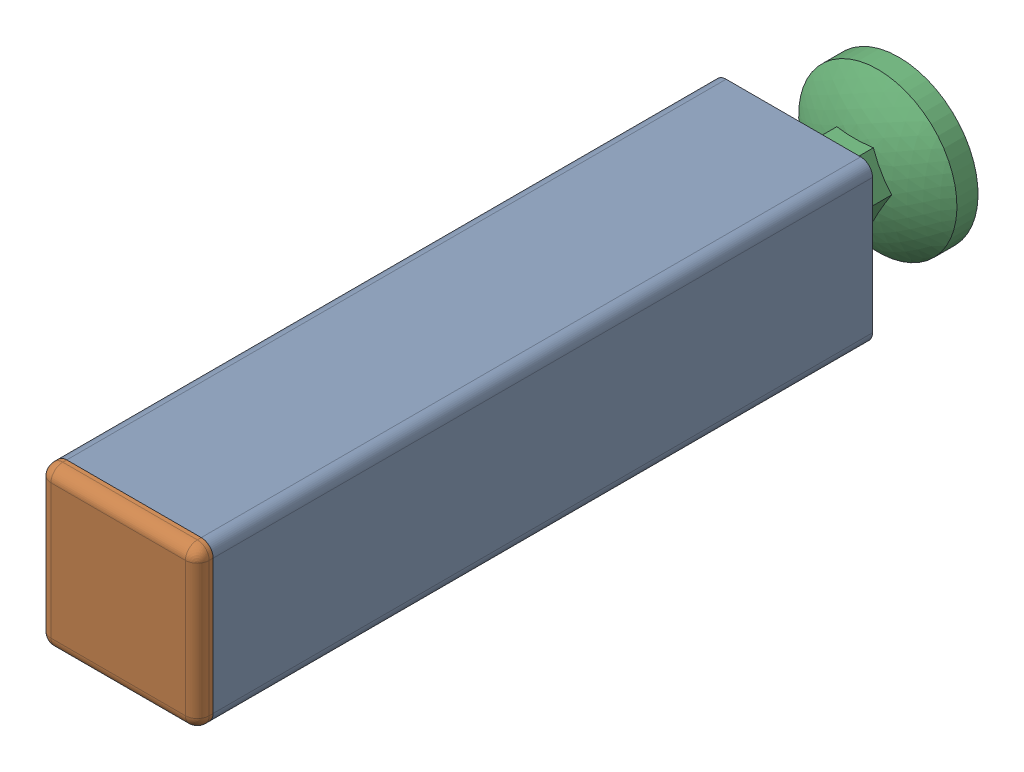
SolidWorks assembly AP_Poteau, configuration Défaut. Lengths in mm.
Overall size (30 30 148).
3 component instances, 3 part files, 5 mates.
Components (placement in the parent):
- Rexroth30x30x125-1: Rexroth30x30x125 [Défaut] at origin size (30 30 125)
- Rexroth-30x30_Chapeau-1: Rexroth-30x30_Chapeau [Défaut] at (0 0 125) size (30 30 3)
- Rexroth-PiedRotul8x30-1: Rexroth-PiedRotul8x30 [Défaut] at (0 0 -20) x (1 0 0) z (0 -1 0) size (30 65 30)
Mates (geometry in assembly coordinates):
- Coïncidente1: coincident anti-aligned: plane of Rexroth30x30x125-1 through (12.75 12.75 0) normal (0 0 -1); plane of Rexroth-PiedRotul8x30-1 through (0 0 0) normal (0 0 1)
- Distance1: distance = 15 mm: plane of Rexroth30x30x125-1 through (-15 12.75 125) normal (-1 0 0); moEndPointRef_w of Rexroth-PiedRotul8x30-1
- Distance2: distance = 15 mm: plane of Rexroth30x30x125-1 through (-12.75 -15 125) normal (0 -1 0); moEndPointRef_w of Rexroth-PiedRotul8x30-1
- Coïncidente4: coincident aligned: line of Rexroth30x30x125-1 through (-12.75 -15 125) axis (1 0 0); line of Rexroth-30x30_Chapeau-1 through (-12.75 -15 125) axis (1 0 0)
- Coïncidente5: coincident aligned: line of Rexroth30x30x125-1 through (15 -12.75 125) axis (0 1 0); line of Rexroth-30x30_Chapeau-1 through (15 -12.75 125) axis (0 1 0)
